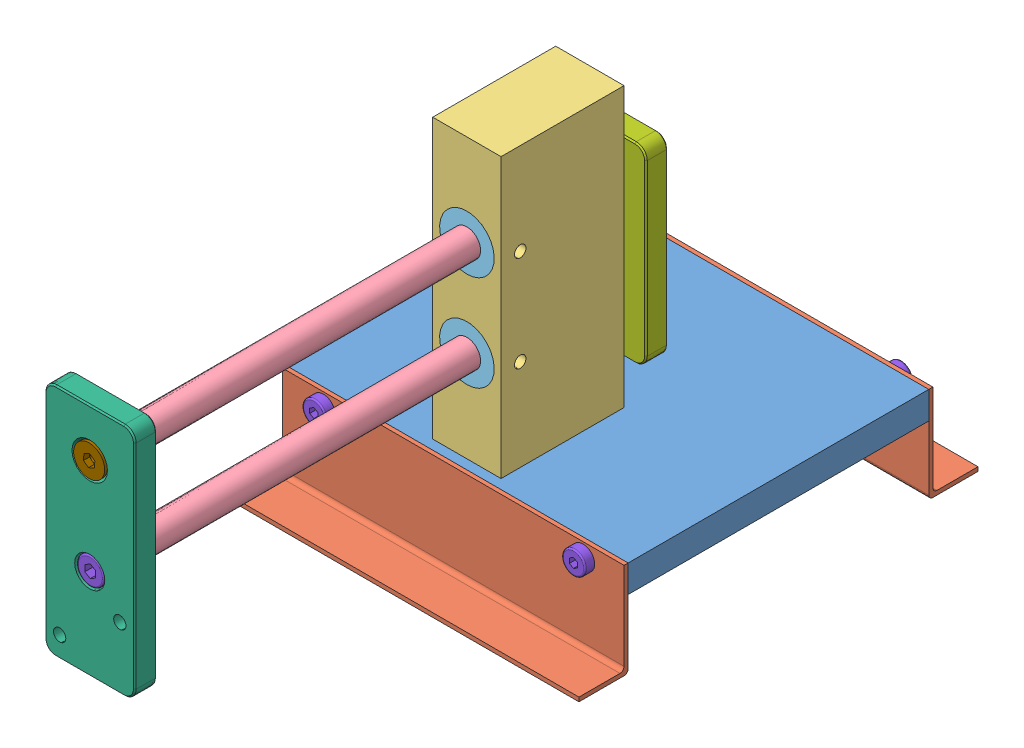
SolidWorks assembly cum_s1, configuration Default. Lengths in mm.
Overall size (125 137 262.72).
22 component instances, 9 part files, 50 mates.
Components (placement in the parent):
- tam_de-1: tam_de [Default] at (55.7373 162.4347 98.3877) size (125 10 110)
- khoi_do-1: khoi_do [Default] at (118.2373 137.4347 153.3877) x (0 0 1) z (0 -1 0) size (18 125 35)
- khoi_do-2: khoi_do [Default] at (-6.7627 137.4347 43.3877) x (0 0 -1) z (0 -1 0) size (18 125 35)
- con_truot-4: con_truot [Default] at (43.2373 223.4347 127.3877) x (0 0 1) z (0 1 0) size (45 25 102)
- chot_dan_huong-1: chot_dan_huong [Default] at (55.7373 240.9347 279.8877) x (0.265953 0.963986 0) z (-0.963986 0.265953 0) size (10 175 10)
- bat_lot-3: bat_lot [Default] at (55.7373 240.9347 149.8877) x (0.167613 0.985853 0) z (-0.985853 0.167613 0) size (20 10 20)
- bat_lot-4: bat_lot [Default] at (55.7373 205.9347 149.8877) x (0.167613 0.985853 0) z (-0.985853 0.167613 0) size (20 10 20)
- bat_lot-5: bat_lot [Default] at (55.7373 240.9347 104.8877) x (-0.554759 0.832011 0) z (0.832011 0.554759 0) size (20 10 20)
- bat_lot-6: bat_lot [Default] at (55.7373 205.9347 104.8877) x (0.395512 -0.918461 0) z (-0.918461 -0.395512 0) size (20 10 20)
- chot_dan_huong-2: chot_dan_huong [Default] at (55.7373 205.9347 279.8877) x (0.187291 -0.982304 0) z (0.982304 0.187291 0) size (10 175 10)
- ban_canh_truoc-1: ban_canh_truoc [Default] at (55.7373 215.4347 279.8877) x (1 0 0) z (0 -1 0) size (33 8 86)
- ban_canh_sau-1: ban_canh_sau [Default] at (55.7373 223.4347 104.8877) x (-1 0 0) z (0 -1 0) size (41 8 70)
- socket head thin cap screw_din-14: socket head thin cap screw_din [DIN 7984 - M5 x 8 --- 5.6N] at (8.2373 167.4347 38.3877) x (0 0 1) z (-1 0 0) size (11.5 8.5 8.5)
- socket head thin cap screw_din-16: socket head thin cap screw_din [DIN 7984 - M5 x 8 --- 5.6N] at (8.2373 167.4347 158.3877) x (0 0 -1) z (1 0 0) size (11.5 8.5 8.5)
- socket head thin cap screw_din-17: socket head thin cap screw_din [DIN 7984 - M5 x 8 --- 5.6N] at (103.2373 167.4347 158.3877) x (0 0 -1) z (1 0 0) size (11.5 8.5 8.5)
- socket head thin cap screw_din-18: socket head thin cap screw_din [DIN 7984 - M5 x 8 --- 5.6N] at (63.2373 164.6347 109.3877) x (0 1 0) z (0 0 1) size (11.5 8.5 8.5)
- socket head thin cap screw_din-19: socket head thin cap screw_din [DIN 7984 - M5 x 8 --- 5.6N] at (48.2373 164.6347 145.3877) x (0 1 0) z (0 0 1) size (11.5 8.5 8.5)
- socket head thin cap screw_din-22: socket head thin cap screw_din [DIN 7984 - M5 x 8 --- 5.6N] at (103.2373 167.4347 38.3877) x (0 0 1) z (-1 0 0) size (11.5 8.5 8.5)
- socket head thin cap screw_din-23: socket head thin cap screw_din [DIN 7984 - M6 x 10 --- 7N] at (55.7373 205.9347 97.0877) x (0 0 1) z (-1 0 0) size (14 10 10)
- socket head thin cap screw_din-24: socket head thin cap screw_din [DIN 7984 - M6 x 10 --- 7N] at (55.7373 205.6984 287.6877) x (0 0 -1) z (1 0 0) size (14 10 10)
- socket csink head cap screw 10642_din-2: socket csink head cap screw 10642_din [EN ISO 10642 - M6 x 8 - 8N] at (55.7373 240.9347 96.6677) x (0 0 1) z (-0.997818 -0.066017 0) size (8 11.34 11.34)
- socket csink head cap screw 10642_din-3: socket csink head cap screw 10642_din [EN ISO 10642 - M6 x 8 - 8N] at (55.7373 240.9347 288.1077) x (0 0 -1) z (0.996151 -0.087658 0) size (8 11.34 11.34)
Mates (geometry in assembly coordinates):
- Parallel1: parallel aligned: plane of tam_de-1 through (-6.7627 172.4347 153.3877) normal (0 0 1); plane of khoi_do-1 through (-6.7627 172.4347 154.8877) normal (0 0 1)
- Concentric1: concentric aligned: cylinder of tam_de-1 through (8.2373 167.4347 153.3877) axis (0 0 1) radius 2.1; circle of khoi_do-1
- Concentric2: concentric aligned: circle of tam_de-1; circle of khoi_do-1
- Coincident1: coincident anti-aligned: plane of tam_de-1 through (-6.7627 172.4347 153.3877) normal (0 0 1); plane of khoi_do-1 through (-6.7627 137.4347 153.3877) normal (0 0 -1)
- Parallel2: parallel anti-aligned: plane of tam_de-1 through (-6.7627 172.4347 43.3877) normal (0 0 -1); plane of khoi_do-2 through (118.2373 137.4347 43.3877) normal (0 0 1)
- Concentric3: concentric aligned: circle of tam_de-1; cylinder of khoi_do-2 through (8.2373 167.4347 43.3877) axis (0 0 -1) radius 2.75
- Parallel3: parallel aligned: plane of tam_de-1 through (55.7373 172.4347 98.3877) normal (0 1 0); plane of khoi_do-2 through (118.2373 172.4347 43.3877) normal (0 1 0)
- Coincident2: coincident anti-aligned: plane of tam_de-1 through (-6.7627 172.4347 43.3877) normal (0 0 -1); plane of khoi_do-2 through (118.2373 137.4347 43.3877) normal (0 0 1)
- Parallel8: parallel anti-aligned: plane of tam_de-1 through (55.7373 172.4347 98.3877) normal (0 1 0); plane of con_truot-4 through (68.2373 172.4347 104.8877) normal (0 -1 0)
- Concentric8: concentric anti-aligned: circle of tam_de-1; circle of con_truot-4
- Concentric9: concentric anti-aligned: circle of tam_de-1; cylinder of con_truot-4 through (48.2373 172.4347 145.3877) axis (0 -1 0) radius 2.1
- Coincident6: coincident anti-aligned: plane of tam_de-1 through (55.7373 172.4347 98.3877) normal (0 1 0); plane of con_truot-4 through (68.2373 172.4347 104.8877) normal (0 -1 0)
- Concentric12: concentric anti-aligned: circle of con_truot-4; circle of bat_lot-3
- Coincident9: coincident anti-aligned: plane of con_truot-4 through (55.7373 240.9347 147.8877) normal (0 0 1); plane of bat_lot-3 through (55.7373 240.9347 147.8877) normal (0 0 -1)
- Concentric13: concentric anti-aligned: cylinder of con_truot-4 through (55.7373 205.9347 178.8877) axis (0 0 -1) radius 6; cylinder of bat_lot-4 through (55.7373 205.9347 139.8877) axis (0 0 1) radius 6
- Coincident10: coincident aligned: plane of con_truot-4 through (68.2373 274.4347 149.8877) normal (0 0 1); plane of bat_lot-4 through (55.7373 205.9347 149.8877) normal (0 0 1)
- Concentric14: concentric aligned: cylinder of con_truot-4 through (55.7373 240.9347 178.8877) axis (0 0 -1) radius 6; cylinder of bat_lot-5 through (55.7373 240.9347 114.8877) axis (0 0 -1) radius 6
- Coincident11: coincident aligned: plane of con_truot-4 through (68.2373 274.4347 104.8877) normal (0 0 -1); plane of bat_lot-5 through (55.7373 240.9347 104.8877) normal (0 0 -1)
- Concentric15: concentric aligned: cylinder of con_truot-4 through (55.7373 205.9347 178.8877) axis (0 0 -1) radius 6; cylinder of bat_lot-6 through (55.7373 205.9347 114.8877) axis (0 0 -1) radius 6
- Coincident13: coincident anti-aligned: plane of con_truot-4 through (55.7373 205.9347 106.8877) normal (0 0 -1); plane of bat_lot-6 through (55.7373 205.9347 106.8877) normal (0 0 1)
- Concentric16: concentric anti-aligned: circle of chot_dan_huong-1; circle of bat_lot-3
- Concentric17: concentric anti-aligned: circle of bat_lot-4; circle of chot_dan_huong-2
- Parallel10: parallel aligned: plane of con_truot-4 through (68.2373 274.4347 149.8877) normal (0 0 1); plane of ban_canh_truoc-1 through (55.7373 215.4347 257.6286) normal (0 0 1)
- Concentric18: concentric aligned: cylinder of chot_dan_huong-2 through (55.7373 205.9347 249.6286) axis (0 0 1) radius 2.5; circle of ban_canh_truoc-1
- Concentric19: concentric anti-aligned: circle of chot_dan_huong-1; circle of ban_canh_truoc-1
- Coincident14: coincident aligned: plane of chot_dan_huong-1 through (55.7373 240.9347 249.6286) normal (0 0 1); circle of ban_canh_truoc-1
- Coincident15: coincident aligned: circle of chot_dan_huong-2; plane of ban_canh_truoc-1 through (55.7373 215.4347 249.6286) normal (0 0 -1)
- Parallel11: parallel aligned: plane of con_truot-4 through (68.2373 274.4347 104.8877) normal (0 0 -1); plane of ban_canh_sau-1 through (55.7373 223.4347 66.6286) normal (0 0 -1)
- Concentric20: concentric aligned: circle of chot_dan_huong-2; circle of ban_canh_sau-1
- Concentric23: concentric anti-aligned: circle of chot_dan_huong-1; cylinder of ban_canh_sau-1 through (55.7373 240.9347 66.6286) axis (0 0 1) radius 3.3
- Coincident16: coincident anti-aligned: plane of chot_dan_huong-1 through (55.7373 240.9347 74.6286) normal (0 0 -1); plane of ban_canh_sau-1 through (55.7373 223.4347 74.6286) normal (0 0 1)
- LimitDistance3: limit distance = 0 mm anti-aligned: plane of con_truot-4 through (68.2373 274.4347 104.8877) normal (0 0 -1); plane of ban_canh_sau-1 through (55.7373 223.4347 104.8877) normal (0 0 1)
- Concentric37: concentric aligned: cylinder of khoi_do-2 through (8.2373 167.4347 43.3877) axis (0 0 -1) radius 2.75; cylinder of socket head thin cap screw_din-14 through (8.2373 167.4347 6.6377) axis (0 0 -1) radius 4.25
- Coincident28: coincident anti-aligned: plane of khoi_do-2 through (118.2373 172.4347 41.8877) normal (0 0 -1); plane of socket head thin cap screw_din-14 through (8.2373 171.6847 41.8877) normal (0 0 1)
- Concentric39: concentric aligned: cylinder of khoi_do-1 through (8.2373 167.4347 153.3877) axis (0 0 1) radius 2.75; cylinder of socket head thin cap screw_din-16 through (8.2373 167.4347 190.1377) axis (0 0 1) radius 4.25
- Coincident30: coincident anti-aligned: plane of khoi_do-1 through (-6.7627 172.4347 154.8877) normal (0 0 1); plane of socket head thin cap screw_din-16 through (8.2373 171.6847 154.8877) normal (0 0 -1)
- Concentric40: concentric aligned: cylinder of khoi_do-1 through (103.2373 167.4347 153.3877) axis (0 0 1) radius 2.75; cylinder of socket head thin cap screw_din-17 through (103.2373 167.4347 190.1377) axis (0 0 1) radius 4.25
- Coincident31: coincident anti-aligned: plane of khoi_do-1 through (-6.7627 172.4347 154.8877) normal (0 0 1); plane of socket head thin cap screw_din-17 through (103.2373 171.6847 154.8877) normal (0 0 -1)
- Concentric41: concentric aligned: cylinder of tam_de-1 through (63.2373 172.4347 109.3877) axis (0 -1 0) radius 2.75; cylinder of socket head thin cap screw_din-18 through (63.2373 132.8847 109.3877) axis (0 -1 0) radius 4.25
- Coincident32: coincident anti-aligned: plane of tam_de-1 through (63.2373 168.1347 109.3877) normal (0 -1 0); plane of socket head thin cap screw_din-18 through (58.9873 168.1347 109.3877) normal (0 1 0)
- Concentric42: concentric aligned: cylinder of tam_de-1 through (48.2373 172.4347 145.3877) axis (0 -1 0) radius 2.75; cylinder of socket head thin cap screw_din-19 through (48.2373 132.8847 145.3877) axis (0 -1 0) radius 4.25
- Coincident33: coincident anti-aligned: plane of tam_de-1 through (48.2373 168.1347 145.3877) normal (0 -1 0); plane of socket head thin cap screw_din-19 through (43.9873 168.1347 145.3877) normal (0 1 0)
- Concentric451: concentric aligned: cylinder of khoi_do-2 through (103.2373 167.4347 43.3877) axis (0 0 -1) radius 2.75; cylinder of socket head thin cap screw_din-22 through (103.2373 167.4347 6.6377) axis (0 0 -1) radius 4.25
- Coincident361: coincident anti-aligned: plane of khoi_do-2 through (118.2373 172.4347 41.8877) normal (0 0 -1); plane of socket head thin cap screw_din-22 through (103.2373 171.6847 41.8877) normal (0 0 1)
- Concentric46: concentric anti-aligned: cylinder of ban_canh_sau-1 through (55.7373 205.9347 66.6286) axis (0 0 1) radius 3.3; cylinder of socket head thin cap screw_din-23 through (55.7373 205.9347 35.0786) axis (0 0 -1) radius 5
- Coincident37: coincident anti-aligned: plane of ban_canh_sau-1 through (55.7373 205.9347 70.8286) normal (0 0 -1); plane of socket head thin cap screw_din-23 through (55.7373 210.9347 70.8286) normal (0 0 1)
- Concentric47: concentric aligned: cylinder of ban_canh_truoc-1 through (55.7373 205.6984 253.4286) axis (0 0 1) radius 5.5; cylinder of socket head thin cap screw_din-24 through (55.7373 205.6984 289.1786) axis (0 0 1) radius 5
- Coincident38: coincident anti-aligned: plane of ban_canh_truoc-1 through (55.7373 205.6984 253.4286) normal (0 0 1); plane of socket head thin cap screw_din-24 through (55.7373 210.6984 253.4286) normal (0 0 -1)
- Coincident39: coincident aligned: cone of ban_canh_sau-1 through (55.7373 240.9347 69.8286) axis (0 0 1); cone of socket csink head cap screw 10642_din-2 through (55.7373 240.9347 67.4586) axis (0 0 1)
- Coincident40: coincident aligned: cone of ban_canh_truoc-1 through (55.7373 240.9347 254.4286) axis (0 0 -1); cone of socket csink head cap screw 10642_din-3 through (55.7373 240.9347 256.7986) axis (0 0 -1)
